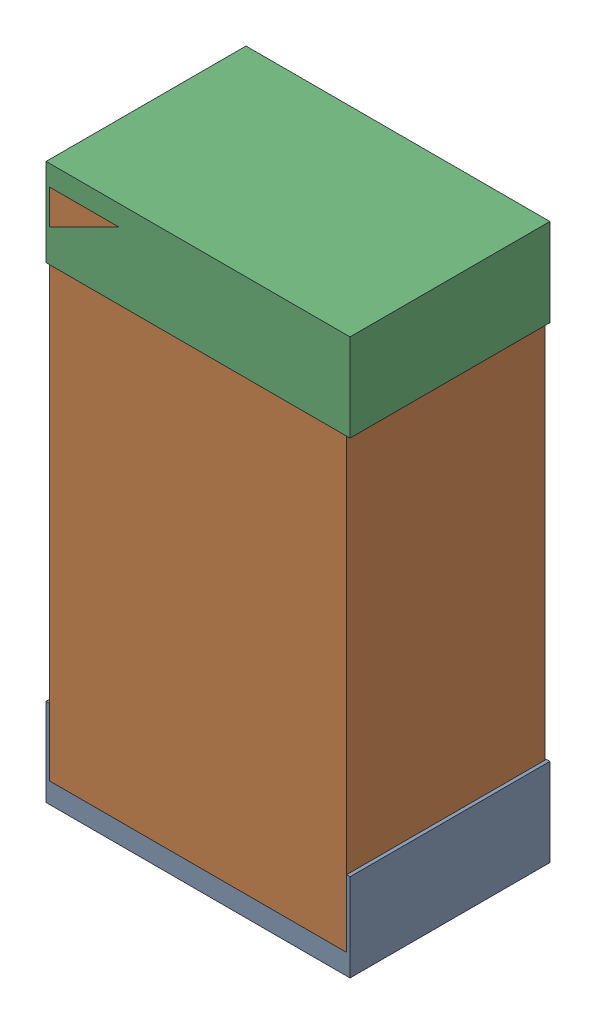
SolidWorks assembly R22Kanaloa_v2.0.0_Motor, configuration Default. Lengths in mm.
Overall size (1.3 2.38 0.85).
6 component instances, 2 part files, 0 mates.
Components (placement in the parent):
- 330415056-1: 330415056 [Default] at (42.418 97.806 -1.9574) size (1.3 0.38 0.85)
  - Extruded_2-1: Extruded_2 [Default] at origin size (1.3 0.38 0.85)
- 334787376-1: 334787376 [Default] at (42.418 98.806 -1.9524) size (1.27 2.2 0.85)
  - Extruded_16-1: Extruded_16 [Default] at origin size (1.27 2.2 0.85)
- 330415056-2: 330415056 [Default] at (42.418 99.806 -1.9574) size (1.3 0.38 0.85)
  - Extruded_2-1: Extruded_2 [Default] at origin size (1.3 0.38 0.85)
